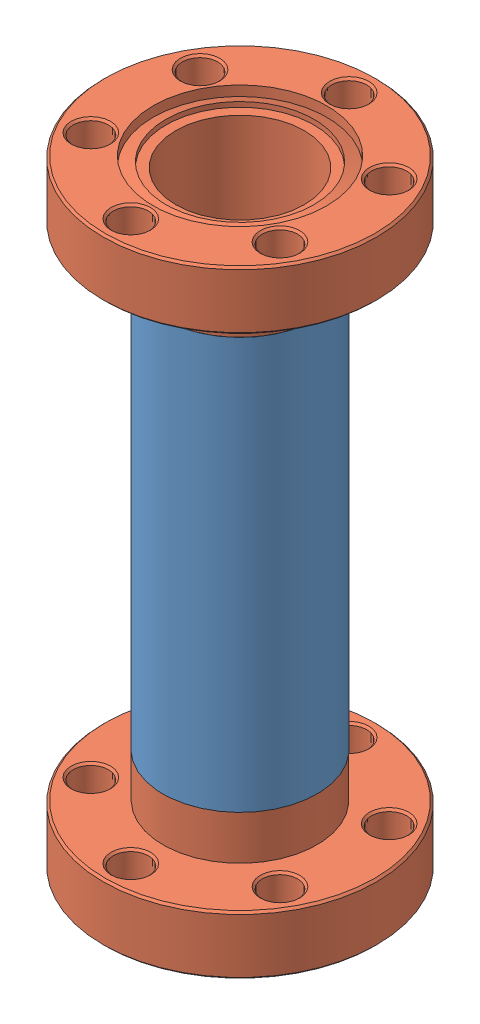
SolidWorks assembly slower bellows, configuration Default. Lengths in mm.
Overall size (33.78 76.2 33.78).
3 component instances, 2 part files, 5 mates.
Components (placement in the parent):
- bellows tube-1: bellows tube [Default] at (8.9079 -18.6235 7.9519) size (19.05 50.8 19.05)
- CF133flange-1: CF133flange [Default] at (8.9079 44.8765 7.9519) x (1 0 0) z (0 1 0) size (33.78 33.78 14.22)
- CF133flange-2: CF133flange [Default] at (8.9079 -31.3235 7.9519) x (1 0 0) z (0 -1 0) size (33.78 33.78 14.22)
Mates (geometry in assembly coordinates):
- Coincident1: coincident anti-aligned: plane of bellows tube-1 through (8.9079 32.1765 7.9519) normal (0 1 0); plane of CF133flange-1 through (8.9079 32.1765 7.9519) normal (0 -1 0)
- Concentric1: concentric aligned: circle of bellows tube-1; circle of CF133flange-1
- Coincident2: coincident anti-aligned: plane of bellows tube-1 through (8.9079 -18.6235 7.9519) normal (0 -1 0); plane of CF133flange-2 through (8.9079 -18.6235 7.9519) normal (0 1 0)
- Concentric2: concentric aligned: circle of bellows tube-1; circle of CF133flange-2
- Concentric3: concentric anti-aligned: circle of CF133flange-1; circle of CF133flange-2
